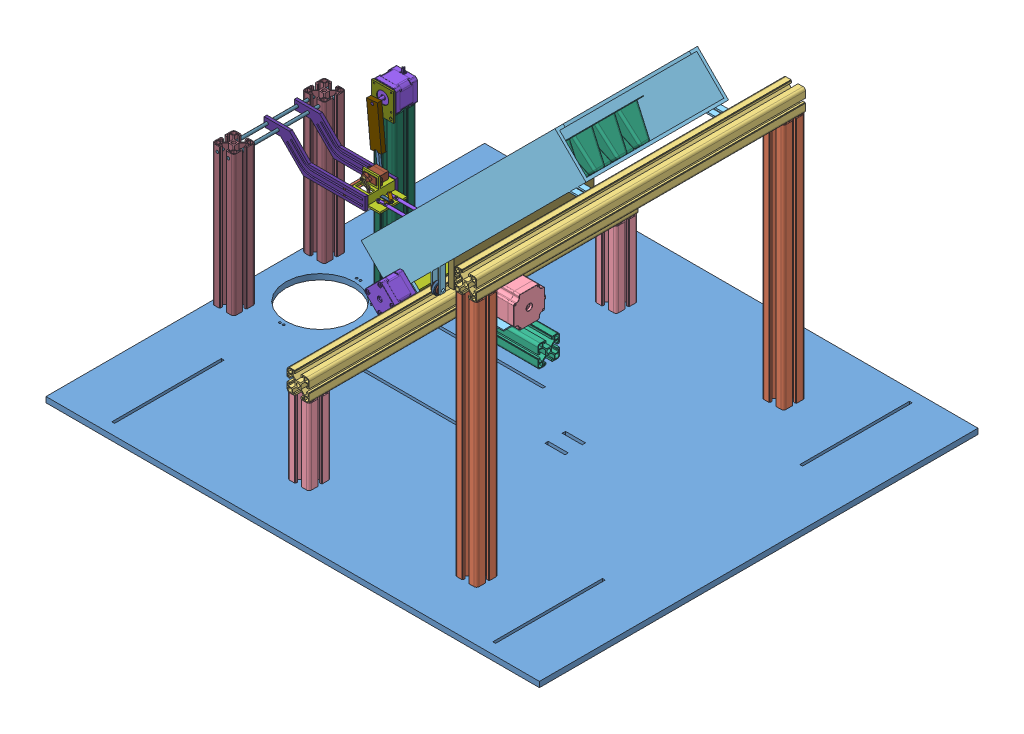
SolidWorks assembly final_mechanism_updated, configuration Default. Lengths in mm.
Overall size (900 557.9 800).
90 component instances, 45 part files, 92 mates.
Components (placement in the parent):
- Assem1-1: Assem1 [Default] at (521.9245 11.6518 -329.9059) size (923.63 667.59 800) (flexible)
  - test_platform-1: test_platform [Default] at (230.5331 526.4519 836.3873) size (900 10 800)
  - sub_assem_1-1: sub_assem_1 [Default] at (-22.5862 285.3896 1012.0904) x (-1 0 0) z (0 0 -1) size (153.18 360.23 146) (hidden, flexible)
    - sapling_cylinder-1: sapling_cylinder [Default] at (46.8806 8.4854 135.7031) size (134 210 146)
    - blade-1: blade [Default] at (44.8168 20.3952 75.7031) x (0.944014 0.329906 0) z (0 0 -1) size (71.09 159.46 120)
    - blade-2: blade [Default] at (48.9445 20.3952 75.7031) x (-0.944014 0.329906 0) z (0 0 1) size (71.09 159.46 120)
  - dsbc-40-300-ppva-n3-2: dsbc-40-300-ppva-n3 [Default] at (345.1649 571.4519 936.3873) x (0 0 1) z (-1 0 0) size (132 54 761.9) (hidden, flexible)
    - dsbc-40-300-ppva-n3_01-1: dsbc-40-300-ppva-n3_01 [Default] at origin size (54 54 430.3)
    - dsbc-40-300-ppva-n3_02-2: dsbc-40-300-ppva-n3_02 [Default] at (0 0 15.0525) x (0.967893 0.251361 0) z (0 0 1) size (40 40 424.9)
    - connecting_rod_1-1: connecting_rod_1 [Default] at (66 0 58.9525) x (0 1 0) z (-1 0 0) size (18 18 132)
  - pneumatic_1_mount-1: pneumatic_1_mount [Default] at (376.9676 570.0281 904.8873) x (0 0 1) z (-1 0 0) size (63 63 68) (hidden)
  - connecting_rod-1: connecting_rod [Default] at (-53.6975 482.9795 1002.3873) x (0.967756 0.251889 0) z (0 0 1) size (385.53 18 4) (hidden)
  - connecting_rod-2: connecting_rod [Default] at (-53.6975 482.9795 866.3873) x (0.967756 0.251889 0) z (0 0 1) size (385.53 18 4) (hidden)
  - pneumatic_cylinder-1: pneumatic_cylinder [Default] at (30.9066 509.0476 990.5463) x (-1 0 0) z (0 -1 0) size (16 16 114) (hidden, flexible)
    - cylinder-1: cylinder [Default] at (30.3735 54.159 45.1726) size (16 16 94)
    - rod-1: rod [Default] at (30.3735 54.159 66.5825) x (-0.909841 -0.414956 0) z (0 0 1) size (12 12 85)
    - rod_end-1: rod_end [Default] at (30.3735 54.159 151.5825) x (0 1 0) z (0 0 -1) size (7 7 18)
  - pneumatic_cylinder-3: pneumatic_cylinder [Default] at (-169.8404 509.0476 882.2284) x (1 0 0) z (0 -1 0) size (16 16 114) (hidden, flexible)
    - cylinder-1: cylinder [Default] at (30.3735 54.159 45.1726) size (16 16 94)
    - rod-1: rod [Default] at (30.3735 54.159 66.5825) x (0.95399 -0.299838 0) z (0 0 1) size (12 12 85)
    - rod_end-1: rod_end [Default] at (30.3735 54.159 151.5825) x (0 1 0) z (0 0 -1) size (7 7 18)
  - connecting_rod_2-1: connecting_rod_2 [Default] at (-139.4669 352.9651 934.3873) x (0.025854 0.999666 0) z (0 0 1) size (71.5 5.5 7) (hidden)
  - connecting_rod_2-2: connecting_rod_2 [Default] at (0.5331 352.9651 934.3873) x (-0.025854 0.999666 0) z (0 0 1) size (71.5 5.5 7) (hidden)
  - rail-1: rail [Default] at (-77.4669 417.2853 914.2207) x (0 0 -1) z (1 0 0) size (12 430 16) (hidden)
  - rail-2: rail [Default] at (-61.4669 417.2853 958.554) x (0 0 1) z (-1 0 0) size (12 430 16) (hidden)
- tray_backward_stands-1: tray_backward_stands [Default] at (1027.8277 998.1038 336.4814) x (1 0 0) z (0 -1 0) size (40 40 450)
- tray_backward_stands-2: tray_backward_stands [Default] at (1027.8277 998.1038 896.4814) x (1 0 0) z (0 -1 0) size (40 40 450)
- tray_backward_top_slider-1: tray_backward_top_slider [Default] at (1027.8277 1018.1038 316.4814) size (40 40 600)
- tray_forward_stands-1: tray_forward_stands [Default] at (722.4576 686.1038 336.4814) x (1 0 0) z (0 -1 0) size (40 40 138)
- tray_forward_stands-2: tray_forward_stands [Default] at (722.4576 686.1038 896.4814) x (1 0 0) z (0 -1 0) size (40 40 138)
- tray_backward_top_slider-2: tray_backward_top_slider [Default] at (722.4576 706.1038 316.4814) size (40 40 600)
- tray_assembly-1: tray_assembly [Default] at (1401.996 981.3028 173.5456) x (0 0 1) z (-0.707107 -0.707107 0) size (310.46 115.88 501.94)
  - seedling_tray_holder-1: seedling_tray_holder [Default] at (362.2271 326.8382 246.3572) size (260 112.02 500)
  - seed_tray_insert1-1: seed_tray_insert1 [Default] at (367.2271 386.8382 486.1542) x (-1 0 0) z (0 0 1) size (253.2 55 327.6)
  - tray_mover-1: tray_mover [Default] at (237.2271 329.3382 716.3572) x (1 0 0) z (0 -0.407707 0.913113) size (250 35 35)
  - nema  17-1: nema  17 [По умолчанию] at (534.2271 329.3382 716.3572) x (0 1 0) z (0 0 1) size (42.3 62 51.35)
  - cheese head screw_as-1: cheese head screw_as [AS-NZS 1427 CH - M5 x 12-N] at (228.9271 329.3382 716.3572) size (15.32 8.5 8.5)
  - v wheel-1: v wheel [Default] at (502.0975 292.5641 251.7186) x (0 0.707107 -0.707107) z (-0.213476 0.690807 0.690807) size (11 21.99 21.99)
    - v wheel outer cover-1: v wheel outer cover [Default] at (5.3844 11.4744 17.147) size (6 21 21)
    - W 625-2RS1-1: W 625-2RS1 [Default] at (5.8844 11.4744 17.147) x (1 0 0) z (0 0.854321 -0.519745) size (5 16 16)
    - W 625-2RS1-2: W 625-2RS1 [Default] at (-0.1156 11.4744 17.147) size (5 16 16)
  - v wheel-3: v wheel [Default] at (252.7372 293.0565 252.2111) x (0 0.707107 -0.707107) z (-0.258016 0.683165 0.683165) size (11 21.99 21.99)
    - v wheel outer cover-1: v wheel outer cover [Default] at (5.3844 11.4744 17.147) size (6 21 21)
    - W 625-2RS1-1: W 625-2RS1 [Default] at (5.8844 11.4744 17.147) x (1 0 0) z (0 0.854321 -0.519745) size (5 16 16)
    - W 625-2RS1-2: W 625-2RS1 [Default] at (-0.1156 11.4744 17.147) size (5 16 16)
  - v wheel-4: v wheel [Default] at (502.7372 310.1767 643.3831) x (0 0.707107 0.707107) z (-0.258016 -0.683165 0.683165) size (11 21.99 21.99)
    - v wheel outer cover-1: v wheel outer cover [Default] at (5.3844 11.4744 17.147) size (6 21 21)
    - W 625-2RS1-1: W 625-2RS1 [Default] at (5.8844 11.4744 17.147) x (1 0 0) z (0 0.854321 -0.519745) size (5 16 16)
    - W 625-2RS1-2: W 625-2RS1 [Default] at (-0.1156 11.4744 17.147) size (5 16 16)
  - v wheel-5: v wheel [Default] at (252.7372 310.1767 643.3831) x (0 0.707107 0.707107) z (-0.258016 -0.683165 0.683165) size (11 21.99 21.99)
    - v wheel outer cover-1: v wheel outer cover [Default] at (5.3844 11.4744 17.147) size (6 21 21)
    - W 625-2RS1-1: W 625-2RS1 [Default] at (5.8844 11.4744 17.147) x (1 0 0) z (0 0.854321 -0.519745) size (5 16 16)
    - W 625-2RS1-2: W 625-2RS1 [Default] at (-0.1156 11.4744 17.147) size (5 16 16)
  - geneva_slider2-1: geneva_slider2 [Default] at (484.7271 298.5539 632.7542) x (-1 0 0) z (0 -0.707107 0.707107) size (255 10 50)
- path_stands-1: path_stands [Default] at (377.4576 803.1038 523.9814) x (1 0 0) z (0 -1 0) size (40 40 255)
- path_stands-2: path_stands [Default] at (377.4576 803.1038 688.9814) x (1 0 0) z (0 -1 0) size (40 40 255)
- paths_rods-1: paths_rods [Default] at (367.4576 793.1038 503.9814) x (0.998361 0.057224 0) z (0.057224 -0.998361 0) size (5 205 5)
- paths_rods-2: paths_rods [Default] at (387.4576 793.1038 503.9814) x (0.98932 0.145759 0) z (0.145759 -0.98932 0) size (5 205 5)
- stepper_stand-1: stepper_stand [Default] at (497.4576 838.1038 515.4814) x (1 0 0) z (0 -1 0) size (40 40 290)
- nema17_clamp-1: nema17_clamp [Default] at (498.4576 853.2278 535.4814) size (40 50 3)
- nema  17-1: nema  17 [По умолчанию] at (498.4576 859.1038 495.4814) x (-1 0 0) z (0 1 0) size (42.3 62 51.35)
- travel_path2-1: travel_path2 [Default] at (440.1353 758.5076 558.4814) size (183.92 57.73 5)
- extension_rods-1: extension_rods [Default] at (473.7633 766.2448 501.6529) x (0.99549 0.09487 0) z (0 0 1) size (20 82.53 8) (flexible)
  - female_extension-1: female_extension [Default] at (33.3924 20.0974 51.8285) size (20 78 8)
  - male_extension-1: male_extension [Default] at (33.3924 -9.4704 49.8285) x (1 0 0) z (0 -1 0) size (16 4 67.5)
- slider_crank2-1: slider_crank2 [Default] at (508.3779 755.0076 555.4814) x (0 -1 0) z (-1 0 0) size (20 68 10)
- travel_path2-2: travel_path2 [Default] at (440.1353 758.5076 613.4814) size (183.92 57.73 5)
- geneva_shaft-2: geneva_shaft [Default] at (758.4617 744.9876 621.4814) x (0 0 -1) z (0 1 0) size (35 15 20)
- Stepper motor NEMA 23HS7430-1: Stepper motor NEMA 23HS7430 [По умолчанию] at (774.0617 744.9876 621.4814) x (0 0 -1) z (1 0 0) size (58.4 56.4 95.6)
- nema23_clamp-1: nema23_clamp [Default] at (772.0617 713.5376 591.4814) x (1 0 0) z (0 -1 0) size (60 60 60)
- geneva_motor_stand-1: geneva_motor_stand [Default] at (742.4576 693.5376 621.4814) x (0 0 -1) z (1 0 0) size (40 40 142)
- gripper-2: gripper [Default] at (509.5518 726.1906 531.1082) size (115.01 38 50) (flexible)
  - gripper_base-1: gripper_base [Default] at (33.8261 21.317 32.3733) size (70 38 50)
  - gripper_arm-1: gripper_arm [Default] at (93.826 26.817 47.3135) x (0 1 0) z (0.001495 0 0.999999) size (5.12 65.01 5.56)
  - gripper_arm-2: gripper_arm [Default] at (93.826 26.817 67.4331) x (0 -1 0) z (0.001495 0 -0.999999) size (5.12 65.01 5.56)
  - gripper_arm_link-1: gripper_arm_link [Default] at (48.0783 29.317 52.3823) x (-0.781521 0 -0.623879) z (0 -1 0) size (20 5 1.5)
  - gripper_arm_link-2: gripper_arm_link [Default] at (48.0783 25.817 62.3643) x (-0.781521 0 0.623879) z (0 -1 0) size (20 5 1.5)
  - gripper_crank-1: gripper_crank [Default] at (57.3304 27.317 54.8733) x (0 0 1) z (0 -1 0) size (15 35 1.5)
  - Tower Pro 9g Micro Servo SG90-1: Tower Pro 9g Micro Servo SG90 [Default] at (17.4261 49.612 57.0533) x (1 0 0) z (0 -1 0) size (36.67 31.5 22.48) (flexible)
    - Tower Pro 9g Micro Servo SG90-1: Tower Pro 9g Micro Servo SG90 [Default] at origin size (36.67 29.95 12.59)
    - SG90 plastic Horn-1: SG90 plastic Horn [Default] at (-1.405 13.16 0) x (0.746006 0 0.66594) z (-0.66594 0 0.746006) size (19.4 4 7.07)
  - gripper_crank2-1: gripper_crank2 [Default] at (25.1835 34.0656 68.2133) x (0.999808 0.019591 0) z (0.019591 -0.999808 0) size (3 2 18)
- flexible_rods-1: flexible_rods [Default] at (454.9576 518.1038 873.5682) size (40 40 400) (hidden)
- flexible_rods-2: flexible_rods [Default] at (1149.9576 518.1038 844.3467) size (40 40 400) (hidden)
- flexible_rods-3: flexible_rods [Default] at (454.9576 518.1038 339.0672) x (-1 0 0) z (0 0 -1) size (40 40 400) (hidden)
- flexible_rods-4: flexible_rods [Default] at (1149.9576 518.1038 448.2789) x (-1 0 0) z (0 0 -1) size (40 40 400) (hidden)
- C-clamp-1: C-clamp [Default] at (1124.9576 486.1038 77.7789) x (0 1 0) z (1 0 0) size (24 54 50) (hidden)
- C-clamp-2: C-clamp [Default] at (429.9576 486.1038 -31.4328) x (0 1 0) z (1 0 0) size (24 54 50) (hidden)
- C-clamp-3: C-clamp [Default] at (1124.9576 486.1038 1214.8467) x (0 1 0) z (1 0 0) size (24 54 50) (hidden)
- C-clamp-4: C-clamp [Default] at (429.9576 486.1038 1244.0682) x (0 1 0) z (1 0 0) size (24 54 50) (hidden)
Mates (geometry in assembly coordinates):
- Coincident6: coincident anti-aligned: plane of Assem1-1/test_platform-1 through (752.4576 548.1038 506.4814) normal (0 1 0); plane of tray_backward_stands-1 through (1043.3277 548.1038 351.9814) normal (0 -1 0)
- Coincident7: coincident anti-aligned: plane of Assem1-1/test_platform-1 through (752.4576 548.1038 506.4814) normal (0 1 0); plane of tray_backward_stands-2 through (1043.3277 548.1038 911.9814) normal (0 -1 0)
- Coincident8: coincident aligned: plane of tray_backward_stands-1 through (1012.3277 548.1038 316.4814) normal (0 0 -1); plane of tray_backward_top_slider-1 through (1043.3277 1033.6038 316.4814) normal (0 0 -1)
- Coincident9: coincident anti-aligned: plane of tray_backward_stands-1 through (1043.3277 998.1038 351.9814) normal (0 1 0); plane of tray_backward_top_slider-1 through (1012.3277 998.1038 916.4814) normal (0 -1 0)
- Coincident10: coincident aligned: plane of tray_backward_stands-1 through (1047.8277 548.1038 340.447) normal (1 0 0); plane of tray_backward_top_slider-1 through (1047.8277 1022.0694 916.4814) normal (1 0 0)
- Coincident11: coincident aligned: plane of tray_backward_stands-2 through (1043.3277 548.1038 916.4814) normal (0 0 1); plane of tray_backward_top_slider-1 through (1043.3277 1033.6038 916.4814) normal (0 0 1)
- Coincident12: coincident aligned: plane of tray_backward_stands-2 through (1047.8277 548.1038 900.447) normal (1 0 0); plane of tray_backward_top_slider-1 through (1047.8277 1022.0694 916.4814) normal (1 0 0)
- Coincident13: coincident anti-aligned: plane of Assem1-1/test_platform-1 through (752.4576 548.1038 506.4814) normal (0 1 0); plane of tray_forward_stands-1 through (737.9576 548.1038 351.9814) normal (0 -1 0)
- Coincident14: coincident anti-aligned: plane of Assem1-1/test_platform-1 through (752.4576 548.1038 506.4814) normal (0 1 0); plane of tray_forward_stands-2 through (737.9576 548.1038 911.9814) normal (0 -1 0)
- Coincident15: coincident anti-aligned: plane of tray_forward_stands-1 through (737.9576 686.1038 351.9814) normal (0 1 0); plane of tray_backward_top_slider-2 through (706.9576 686.1038 916.4814) normal (0 -1 0)
- Coincident16: coincident aligned: plane of tray_forward_stands-1 through (702.4576 548.1038 332.5158) normal (-1 0 0); plane of tray_backward_top_slider-2 through (702.4576 702.1382 916.4814) normal (-1 0 0)
- Coincident17: coincident aligned: plane of tray_forward_stands-1 through (706.9576 548.1038 316.4814) normal (0 0 -1); plane of tray_backward_top_slider-2 through (737.9576 721.6038 316.4814) normal (0 0 -1)
- Coincident18: coincident aligned: plane of tray_forward_stands-2 through (737.9576 548.1038 916.4814) normal (0 0 1); plane of tray_backward_top_slider-2 through (737.9576 721.6038 916.4814) normal (0 0 1)
- Coincident19: coincident aligned: plane of tray_forward_stands-2 through (702.4576 548.1038 900.447) normal (-1 0 0); plane of tray_backward_top_slider-2 through (702.4576 702.1382 916.4814) normal (-1 0 0)
- Coincident20: coincident anti-aligned: plane of tray_backward_top_slider-1 through (1007.8277 1022.0694 916.4814) normal (-1 0 0); plane of tray_assembly-1/seedling_tray_holder-1 through (1007.8277 1021.0694 655.7727) normal (1 0 0)
- Coincident21: coincident aligned: plane of tray_backward_top_slider-1 through (1012.3277 1021.0694 916.4814) normal (0 -1 0); plane of tray_assembly-1/seedling_tray_holder-1 through (1007.8277 1021.0694 655.7727) normal (0 -1 0)
- Coincident23: coincident aligned: plane of tray_backward_top_slider-2 through (727.8429 725.1038 916.4814) normal (-1 0 0); plane of tray_assembly-1/seedling_tray_holder-1 through (727.8429 769.3688 655.7727) normal (-1 0 0)
- Distance1: distance = 90 mm aligned: plane of tray_forward_stands-2 through (737.9576 548.1038 916.4814) normal (0 0 1); plane of Assem1-1/test_platform-1 through (352.4576 548.1038 1006.4814) normal (0 0 1)
- Distance2: distance = 350 mm aligned: plane of tray_forward_stands-2 through (702.4576 548.1038 900.447) normal (-1 0 0); plane of Assem1-1/test_platform-1 through (352.4576 548.1038 206.4814) normal (-1 0 0)
- Coincident28: coincident aligned: plane of tray_backward_stands-2 through (1012.3277 548.1038 916.4814) normal (0 0 1); plane of tray_forward_stands-2 through (706.9576 548.1038 916.4814) normal (0 0 1)
- Coincident40: coincident anti-aligned: plane of Assem1-1/test_platform-1 through (752.4576 548.1038 506.4814) normal (0 1 0); plane of path_stands-2 through (392.9576 548.1038 704.4814) normal (0 -1 0)
- Coincident41: coincident aligned: plane of Assem1-1/rail-1 through (460.4576 538.1038 668.9814) normal (0 0 -1); plane of path_stands-2 through (361.9576 548.1038 668.9814) normal (0 0 -1)
- Coincident43: coincident anti-aligned: plane of Assem1-1/test_platform-1 through (752.4576 548.1038 506.4814) normal (0 1 0); plane of path_stands-1 through (392.9576 548.1038 539.4814) normal (0 -1 0)
- Coincident44: coincident aligned: plane of path_stands-1 through (357.4576 548.1038 527.947) normal (-1 0 0); plane of path_stands-2 through (357.4576 548.1038 685.0158) normal (-1 0 0)
- Coincident45: coincident aligned: plane of Assem1-1/rail-2 through (444.4576 538.1038 543.9814) normal (0 0 1); plane of path_stands-1 through (361.9576 548.1038 543.9814) normal (0 0 1)
- Distance6: distance = 5 mm aligned: plane of path_stands-1 through (357.4576 548.1038 527.947) normal (-1 0 0); plane of Assem1-1/test_platform-1 through (352.4576 548.1038 206.4814) normal (-1 0 0)
- Concentric2: concentric anti-aligned: cylinder of path_stands-2 through (367.4576 793.1038 668.9814) axis (0 0 1) radius 2.5; cylinder of paths_rods-1 through (367.4576 793.1038 708.9814) axis (0 0 -1) radius 2.5
- Coincident47: coincident aligned: plane of path_stands-2 through (361.9576 548.1038 708.9814) normal (0 0 1); plane of paths_rods-1 through (367.4576 793.1038 708.9814) normal (0 0 1)
- Concentric3: concentric anti-aligned: cylinder of path_stands-2 through (387.4576 793.1038 668.9814) axis (0 0 1) radius 2.5; cylinder of paths_rods-2 through (387.4576 793.1038 708.9814) axis (0 0 -1) radius 2.5
- Coincident48: coincident aligned: plane of path_stands-2 through (392.9576 548.1038 708.9814) normal (0 0 1); plane of paths_rods-2 through (387.4576 793.1038 708.9814) normal (0 0 1)
- Coincident49: coincident anti-aligned: plane of Assem1-1/test_platform-1 through (752.4576 548.1038 506.4814) normal (0 1 0); plane of stepper_stand-1 through (512.9576 548.1038 530.9814) normal (0 -1 0)
- Coincident50: coincident: plane of Assem1-1/test_platform-1 through (792.4576 548.1038 535.4814) normal (0 0 1); line of stepper_stand-1 through (481.9576 548.1038 535.4814) axis (0 1 0)
- Distance7: distance = 80 mm anti-aligned: plane of stepper_stand-1 through (477.4576 548.1038 519.447) normal (-1 0 0); plane of path_stands-1 through (397.4576 548.1038 527.947) normal (1 0 0)
- Coincident52: coincident aligned: plane of stepper_stand-1 through (477.4576 548.1038 519.447) normal (-1 0 0); plane of nema  17-1 through (477.4576 859.1038 535.4814) normal (-1 0 0)
- Coincident53: coincident aligned: plane of stepper_stand-1 through (481.9576 548.1038 535.4814) normal (0 0 1); plane of nema  17-1 through (498.4576 859.1038 535.4814) normal (0 0 1)
- Coincident54: coincident anti-aligned: plane of stepper_stand-1 through (512.9576 838.1038 530.9814) normal (0 1 0); plane of nema  17-1 through (498.4576 838.1038 535.4814) normal (0 -1 0)
- Concentric4: concentric aligned: cylinder of nema17_clamp-1 through (513.9576 874.6038 538.4814) axis (0 0 -1) radius 1.25; cylinder of nema  17-1 through (513.9576 874.6038 535.4814) axis (0 0 -1) radius 1.25
- Concentric5: concentric aligned: cylinder of nema17_clamp-1 through (482.9576 874.6038 538.4814) axis (0 0 -1) radius 1.25; cylinder of nema  17-1 through (482.9576 874.6038 535.4814) axis (0 0 -1) radius 1.25
- Coincident55: coincident anti-aligned: plane of nema17_clamp-1 through (498.4576 853.2278 535.4814) normal (0 0 -1); plane of nema  17-1 through (498.4576 859.1038 535.4814) normal (0 0 1)
- Concentric6: concentric aligned: cylinder of paths_rods-2 through (387.4576 793.1038 708.9814) axis (0 0 -1) radius 2.5; cylinder of travel_path2-1 through (387.4576 793.1038 563.4814) axis (0 0 -1) radius 2.5
- Concentric7: concentric aligned: cylinder of paths_rods-1 through (367.4576 793.1038 708.9814) axis (0 0 -1) radius 2.5; cylinder of travel_path2-1 through (367.4576 793.1038 563.4814) axis (0 0 -1) radius 2.5
- Concentric8: concentric aligned: cylinder of nema  17-1 through (498.4576 859.1038 557.4814) axis (0 0 -1) radius 2.5; cylinder of extension_rods-1/female_extension-1 through (498.4576 859.1038 557.4814) axis (0 0 -1) radius 2.5
- Coincident56: coincident aligned: plane of nema  17-1 through (498.4576 859.1038 557.4814) normal (0 0 1); plane of extension_rods-1/female_extension-1 through (488.977 853.1776 557.4814) normal (0 0 1)
- PathMate1: path: point of slider_crank2-1; curve of travel_path2-1; curve of travel_path2-1
- Concentric9: concentric aligned: cylinder of extension_rods-1/male_extension-1 through (508.3779 755.0076 545.4814) axis (0 0 1) radius 1.5; cylinder of slider_crank2-1 through (508.3779 755.0076 550.4814) axis (0 0 1) radius 1.5
- Coincident57: coincident anti-aligned: plane of extension_rods-1/male_extension-1 through (507.9035 759.985 555.4814) normal (0 0 1); plane of slider_crank2-1 through (508.3779 755.0076 555.4814) normal (0 0 -1)
- Concentric12: concentric aligned: cylinder of paths_rods-2 through (387.4576 793.1038 708.9814) axis (0 0 -1) radius 2.5; cylinder of travel_path2-2 through (387.4576 793.1038 618.4814) axis (0 0 -1) radius 2.5
- Concentric13: concentric aligned: cylinder of paths_rods-1 through (367.4576 793.1038 708.9814) axis (0 0 -1) radius 2.5; cylinder of travel_path2-2 through (367.4576 793.1038 618.4814) axis (0 0 -1) radius 2.5
- Coincident60: coincident anti-aligned: plane of tray_assembly-1/geneva_slider2-1 through (753.4617 764.9876 655.7727) normal (1 0 0); plane of geneva_shaft-2 through (753.4617 744.9876 621.4814) normal (-1 0 0)
- Distance8: distance = 0 mm: cylinder of geneva_shaft-2 through (753.4617 744.9876 621.4814) axis (1 0 0) radius 10; plane of tray_assembly-1/geneva_slider2-1 through (753.4617 744.9876 663.2727) normal (0 -1 0)
- Tangent3: tangent anti-aligned: plane of tray_assembly-1/geneva_slider2-1 through (753.4617 744.9876 658.2727) normal (0 0 -1); cylinder of geneva_shaft-2 through (743.4617 744.9876 601.4814) axis (1 0 0) radius 2.5
- Concentric14: concentric aligned: cylinder of geneva_shaft-2 through (753.4617 744.9876 621.4814) axis (1 0 0) radius 2.5; cylinder of Stepper motor NEMA 23HS7430-1 through (753.4617 744.9876 621.4814) axis (1 0 0) radius 3.175
- Coincident61: coincident aligned: plane of geneva_shaft-2 through (753.4617 744.9876 621.4814) normal (-1 0 0); plane of Stepper motor NEMA 23HS7430-1 through (753.4617 744.9876 621.4814) normal (-1 0 0)
- Concentric15: concentric anti-aligned: cylinder of Stepper motor NEMA 23HS7430-1 through (774.0617 768.5376 645.0314) axis (1 0 0) radius 2.5; cylinder of nema23_clamp-1 through (832.0617 768.5376 645.0314) axis (-1 0 0) radius 2.5
- Coincident62: coincident anti-aligned: plane of Stepper motor NEMA 23HS7430-1 through (774.0617 744.9876 621.4814) normal (-1 0 0); plane of nema23_clamp-1 through (774.0617 773.5376 651.4814) normal (1 0 0)
- Concentric16: concentric anti-aligned: cylinder of Stepper motor NEMA 23HS7430-1 through (774.0617 721.4376 597.9314) axis (1 0 0) radius 2.5; cylinder of nema23_clamp-1 through (832.0617 721.4376 597.9314) axis (-1 0 0) radius 2.5
- Coincident63: coincident anti-aligned: plane of tray_backward_top_slider-2 through (742.4576 710.0694 916.4814) normal (1 0 0); plane of geneva_motor_stand-1 through (742.4576 709.0376 605.9814) normal (-1 0 0)
- Coincident64: coincident anti-aligned: plane of nema23_clamp-1 through (772.0617 713.5376 651.4814) normal (0 -1 0); plane of geneva_motor_stand-1 through (884.4576 713.5376 636.9814) normal (0 1 0)
- Distance9: distance = 10 mm aligned: plane of geneva_motor_stand-1 through (884.4576 697.5032 641.4814) normal (0 0 1); plane of nema23_clamp-1 through (772.0617 713.5376 651.4814) normal (0 0 1)
- Parallel2: parallel aligned: plane of tray_backward_top_slider-2 through (737.9576 686.1038 916.4814) normal (0 -1 0); plane of geneva_motor_stand-1 through (884.4576 673.5376 636.9814) normal (0 -1 0)
- Distance10: distance = 275 mm aligned: plane of geneva_motor_stand-1 through (884.4576 697.5032 641.4814) normal (0 0 1); plane of tray_forward_stands-2 through (737.9576 548.1038 916.4814) normal (0 0 1)
- Concentric17: concentric anti-aligned: cylinder of slider_crank2-1 through (508.3779 750.0076 618.4814) axis (0 0 -1) radius 1.5; cylinder of gripper-2/gripper_base-1 through (508.3779 750.0076 563.4814) axis (0 0 1) radius 1.5
- Concentric18: concentric anti-aligned: cylinder of slider_crank2-1 through (508.3779 760.0076 618.4814) axis (0 0 -1) radius 1.5; cylinder of gripper-2/gripper_base-1 through (508.3779 760.0076 563.4814) axis (0 0 1) radius 1.5
- Coincident70: coincident anti-aligned: plane of travel_path2-1 through (440.1353 758.5076 563.4814) normal (0 0 1); plane of gripper-2/gripper_base-1 through (543.3779 747.5076 563.4814) normal (0 0 -1)
- Distance11: distance = 0 mm: plane of tray_assembly-1/geneva_slider2-1 through (753.4617 744.9876 653.2727) normal (0 -1 0); cylinder of geneva_shaft-2 through (743.4617 744.9876 601.4814) axis (1 0 0) radius 2.5
- Parallel3: parallel aligned: plane of geneva_shaft-2 through (753.4617 749.9876 601.4814) normal (0 1 0); plane of nema23_clamp-1 through (772.0617 773.5376 651.4814) normal (0 1 0)
- Coincident71: coincident anti-aligned: plane of Assem1-1/test_platform-1 through (752.4576 538.1038 506.4814) normal (0 -1 0); plane of flexible_rods-1 through (439.4576 538.1038 1273.5682) normal (0 1 0)
- Tangent5: tangent anti-aligned: plane of Assem1-1/test_platform-1 through (457.4576 548.1038 986.4814) normal (-1 0 0); cylinder of flexible_rods-1 through (454.9576 498.1038 883.5682) axis (0 1 0) radius 2.5
- Tangent6: tangent anti-aligned: plane of Assem1-1/test_platform-1 through (457.4576 548.1038 986.4814) normal (-1 0 0); cylinder of flexible_rods-1 through (454.9576 498.1038 933.5682) axis (0 1 0) radius 2.5
- Coincident73: coincident anti-aligned: plane of Assem1-1/test_platform-1 through (752.4576 538.1038 506.4814) normal (0 -1 0); plane of flexible_rods-2 through (1165.4576 538.1038 1244.3467) normal (0 1 0)
- Tangent7: tangent: circle of Assem1-1/test_platform-1; circle of flexible_rods-2
- Tangent8: tangent anti-aligned: plane of Assem1-1/test_platform-1 through (1152.4576 548.1038 986.4814) normal (-1 0 0); cylinder of flexible_rods-2 through (1149.9576 498.1038 904.3467) axis (0 1 0) radius 2.5
- Coincident75: coincident anti-aligned: plane of flexible_rods-3 through (470.4576 538.1038 -60.9328) normal (0 1 0); plane of Assem1-1/test_platform-1 through (752.4576 538.1038 506.4814) normal (0 -1 0)
- Tangent9: tangent anti-aligned: plane of Assem1-1/test_platform-1 through (452.4576 548.1038 226.4814) normal (1 0 0); cylinder of flexible_rods-3 through (454.9576 498.1038 279.0672) axis (0 1 0) radius 2.5
- Tangent10: tangent anti-aligned: plane of Assem1-1/test_platform-1 through (452.4576 548.1038 226.4814) normal (1 0 0); cylinder of flexible_rods-3 through (454.9576 498.1038 329.0672) axis (0 1 0) radius 2.5
- Tangent11: tangent anti-aligned: plane of Assem1-1/test_platform-1 through (1152.4576 548.1038 226.4814) normal (-1 0 0); cylinder of flexible_rods-4 through (1149.9576 498.1038 388.2789) axis (0 1 0) radius 2.5
- Tangent12: tangent anti-aligned: plane of Assem1-1/test_platform-1 through (1152.4576 548.1038 226.4814) normal (-1 0 0); cylinder of flexible_rods-4 through (1149.9576 498.1038 438.2789) axis (0 1 0) radius 2.5
- Coincident76: coincident anti-aligned: plane of Assem1-1/test_platform-1 through (752.4576 538.1038 506.4814) normal (0 -1 0); plane of flexible_rods-4 through (1134.4576 538.1038 48.2789) normal (0 1 0)
- Concentric19: concentric anti-aligned: cylinder of flexible_rods-4 through (1164.9576 498.1038 97.2789) axis (0 1 0) radius 2.5; cylinder of C-clamp-1 through (1164.9576 498.1048 97.2789) axis (0 -1 0) radius 2.25
- Concentric20: concentric anti-aligned: cylinder of flexible_rods-4 through (1134.9576 498.1038 58.2789) axis (0 1 0) radius 2.5; cylinder of C-clamp-1 through (1134.9576 498.1048 58.2789) axis (0 -1 0) radius 2.25
- Coincident78: coincident anti-aligned: plane of flexible_rods-4 through (1134.4576 498.1038 48.2789) normal (0 -1 0); plane of C-clamp-1 through (1174.9576 498.1038 67.7789) normal (0 1 0)
- Concentric21: concentric anti-aligned: cylinder of flexible_rods-2 through (1164.9576 498.1038 1234.3467) axis (0 1 0) radius 2.5; cylinder of C-clamp-3 through (1164.9576 498.1048 1234.3467) axis (0 -1 0) radius 2.25
- Concentric22: concentric anti-aligned: cylinder of flexible_rods-2 through (1134.9576 498.1038 1195.3467) axis (0 1 0) radius 2.5; cylinder of C-clamp-3 through (1134.9576 498.1048 1195.3467) axis (0 -1 0) radius 2.25
- Coincident79: coincident anti-aligned: plane of flexible_rods-2 through (1165.4576 498.1038 1244.3467) normal (0 -1 0); plane of C-clamp-3 through (1174.9576 498.1038 1204.8467) normal (0 1 0)
- Coincident80: coincident anti-aligned: plane of flexible_rods-1 through (439.4576 498.1038 1273.5682) normal (0 -1 0); plane of C-clamp-4 through (479.9576 498.1038 1271.0682) normal (0 1 0)
- Coincident81: coincident anti-aligned: plane of flexible_rods-3 through (439.4576 498.1038 -60.9328) normal (0 -1 0); plane of C-clamp-2 through (479.9576 498.1038 -41.4328) normal (0 1 0)
- Concentric23: concentric anti-aligned: cylinder of flexible_rods-3 through (439.9576 498.1038 -11.9328) axis (0 1 0) radius 2.5; cylinder of C-clamp-2 through (439.9576 498.1048 -11.9328) axis (0 -1 0) radius 2.25
- Concentric24: concentric anti-aligned: cylinder of flexible_rods-3 through (469.9576 498.1038 -50.9328) axis (0 1 0) radius 2.5; cylinder of C-clamp-2 through (469.9576 498.1048 -50.9328) axis (0 -1 0) radius 2.25
- Concentric25: concentric anti-aligned: cylinder of flexible_rods-1 through (439.9576 498.1038 1224.5682) axis (0 1 0) radius 2.5; cylinder of C-clamp-4 through (439.9576 498.1048 1224.5682) axis (0 -1 0) radius 2.25
- Concentric26: concentric anti-aligned: cylinder of flexible_rods-1 through (469.9576 498.1038 1263.5682) axis (0 1 0) radius 2.5; cylinder of C-clamp-4 through (469.9576 498.1048 1263.5682) axis (0 -1 0) radius 2.25
- Coincident82: coincident anti-aligned: plane of travel_path2-2 through (440.1353 758.5076 613.4814) normal (0 0 -1); plane of gripper-2/gripper_base-1 through (543.3779 747.5076 613.4814) normal (0 0 1)
- Coincident84: coincident aligned: plane of travel_path2-1 through (546.3779 766.5076 563.4814) normal (1 0 0); plane of gripper-2/gripper_base-1 through (546.3779 750.5076 613.4814) normal (1 0 0)
